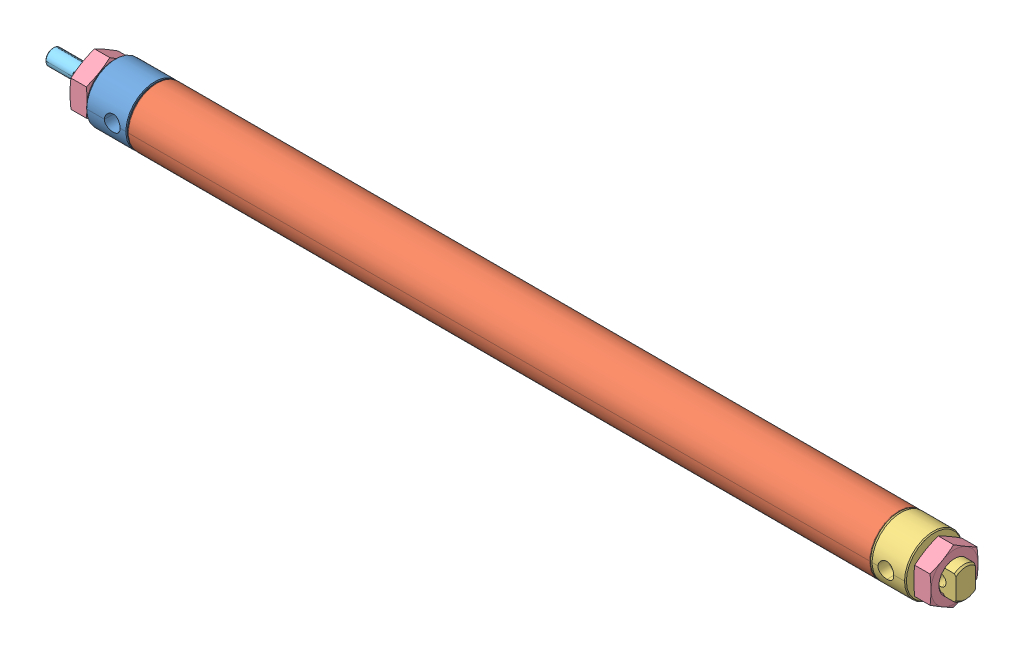
SolidWorks assembly SR_2422_DP, configuration Default. Lengths in mm.
Overall size (739.9 46.85 49.1).
6 component instances, 5 part files, 0 mates.
Components (placement in the parent):
- _24R000_0_rod_guide_4-1: _24R000_0_rod_guide_4 [Default] at origin size (60.33 46.85 46.85)
- _24R_23_73350SR_6-1: _24R_23_73350SR_6 [Default] at (53.3908 0 0) size (604.74 46.85 46.85)
- _24P0000_rear_head_8-1: _24P0000_rear_head_8 [Default] at (649.351 0 0) size (60.33 46.85 46.96)
- _D_1331_10-1: _D_1331_10 [Default] at (686.6382 0 0) x (0 0 -1) z (-1 0 0) size (49.1 44 13.97)
- _D_1331_10-2: _D_1331_10 [Default] at (16.6624 0 0) x (0 0 -1) z (1 0 0) size (49.1 44 13.97)
- _SR_2422_DP0000_rod_13-1: _SR_2422_DP0000_rod_13 [Default] at origin size (679.58 44.69 44.69)
